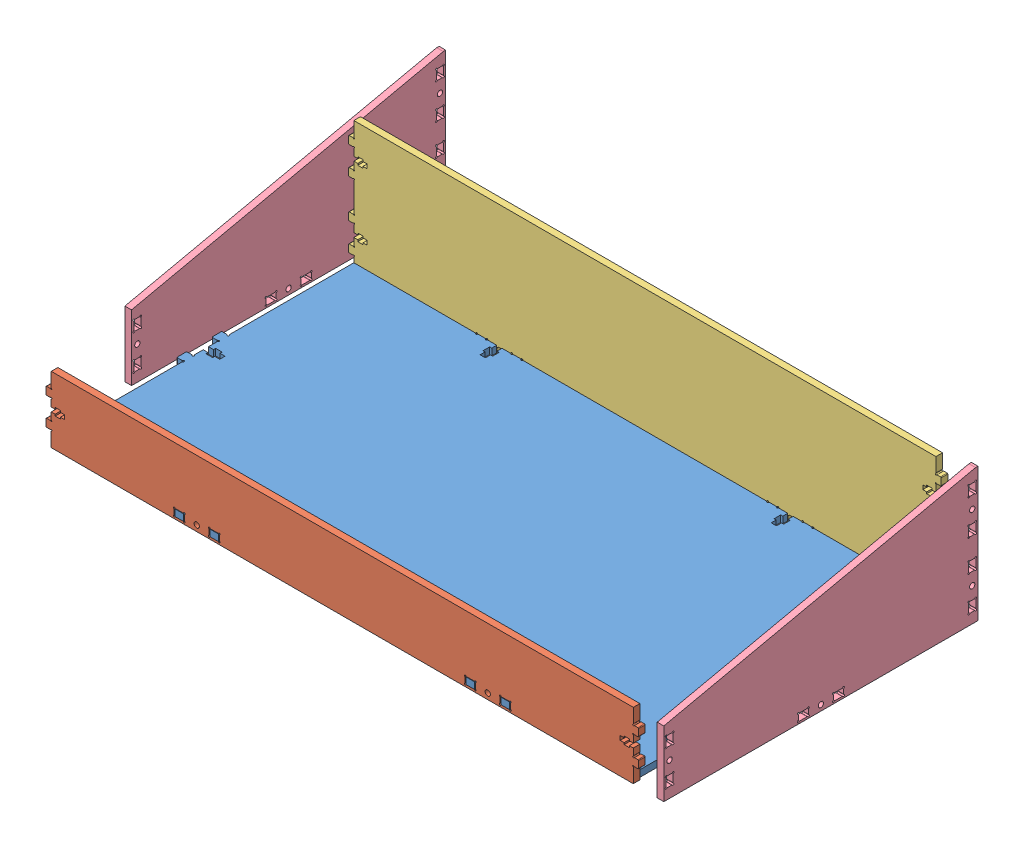
SolidWorks assembly Ensamblaje Box 1, configuration Predeterminado. Lengths in mm.
Overall size (382.95 81.68 247.05).
5 component instances, 4 part files, 6 mates.
Components (placement in the parent):
- RetroPAD - Arcadia v1 - BOX Base 1-1: RetroPAD - Arcadia v1 - BOX Base 1 [Predeterminado] at (-11.537 -36.9955 360.0001) size (360 4 187)
- RetroPAD - Arcadia v1 - BOX Front 1-1: RetroPAD - Arcadia v1 - BOX Front 1 [Predeterminado] at (-11.5381 -18.3456 449.5002) size (358.33 40 4)
- RetroPAD - Arcadia v1 - BOX Back 1-1: RetroPAD - Arcadia v1 - BOX Back 1 [Predeterminado] at (-11.5381 -18.4956 266.5001) size (358.33 80 4)
- RetroPAD - Arcadia v1 - BOX R&L 1-1: RetroPAD - Arcadia v1 - BOX R&L 1 [Predeterminado] at (179.9108 3.7857 359.6823) size (4 80.87 190)
- RetroPAD - Arcadia v1 - BOX R&L 1-2: RetroPAD - Arcadia v1 - BOX R&L 1 [Predeterminado] at (-199.0372 3.6904 302.6282) size (4 80.87 190)
Mates (geometry in assembly coordinates):
- Distancia1: distance = 0 mm anti-aligned: plane of RetroPAD - Arcadia v1 - BOX Base 1-1 through (163.963 -36.9955 374.4662) normal (0 -1 0); plane of RetroPAD - Arcadia v1 - BOX Front 1-1 through (89.297 -36.9955 453.5002) normal (0 1 0)
- Distancia2: distance = 0.15 mm anti-aligned: plane of RetroPAD - Arcadia v1 - BOX Base 1-1 through (163.963 -36.9955 374.4662) normal (0 -1 0); plane of RetroPAD - Arcadia v1 - BOX Back 1-1 through (89.297 -37.1455 270.5001) normal (0 1 0)
- Coincidente3: coincident aligned: plane of RetroPAD - Arcadia v1 - BOX Base 1-1 through (164.463 -32.9955 270.5001) normal (1 0 0); plane of RetroPAD - Arcadia v1 - BOX Front 1-1 through (164.463 -29.7942 453.5002) normal (1 0 0)
- Coincidente4: coincident aligned: plane of RetroPAD - Arcadia v1 - BOX Base 1-1 through (164.463 -32.9955 270.5001) normal (1 0 0); plane of RetroPAD - Arcadia v1 - BOX Back 1-1 through (164.463 -29.9442 270.5001) normal (1 0 0)
- Coincidente5: coincident aligned: plane of RetroPAD - Arcadia v1 - BOX Base 1-1 through (84.563 -32.9955 453.5002) normal (0 0 1); plane of RetroPAD - Arcadia v1 - BOX Front 1-1 through (-187.1413 -29.7942 453.5002) normal (0 0 1)
- Coincidente6: coincident aligned: plane of RetroPAD - Arcadia v1 - BOX Base 1-1 through (84.563 -32.9955 266.5001) normal (0 0 -1); plane of RetroPAD - Arcadia v1 - BOX Back 1-1 through (-187.1413 -29.9442 266.5001) normal (0 0 -1)
